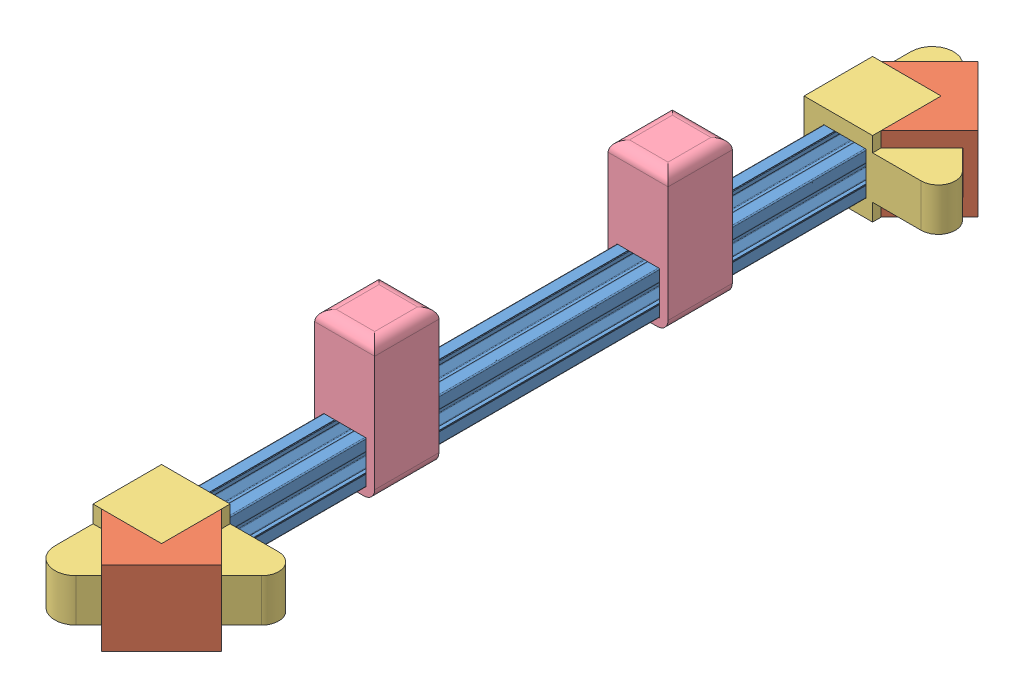
SolidWorks assembly Assem3 - Copy, configuration Varsayılan. Lengths in mm.
Overall size (93.47 78.01 453.33).
9 component instances, 4 part files, 11 mates.
Components (placement in the parent):
- sigma_20x20x1000-1: sigma_20x20x1000 [Varsayılan] at (-144.7646 -85.6017 253.4901) x (0 0 -1) z (1 -0.000076 0) size (350 20 20)
- motortutucular-1: motortutucular [Varsayılan] at (-103.5623 -84.2375 280.9722) x (0.707107 -0.000054 -0.707107) z (-0.707107 0.000054 -0.707107) size (86.65 35 86.65)
  - motortutucuarka-1: motortutucuarka [Varsayılan] at (-25.258 -13.6326 22.249) size (39.6 35 31.98)
  - motortutucuon-1: motortutucuon [Varsayılan] at (-0.4565 -8.6326 49.0416) x (-0.707107 0 0.707107) z (0 1 0) size (62.69 59.86 35)
- motortutucular-2: motortutucular [Varsayılan] at (-103.5625 -86.9722 -123.9919) x (0.707107 -0.000054 0.707107) z (-0.707107 0.000054 0.707107) size (86.65 35 86.65)
  - motortutucuarka-1: motortutucuarka [Varsayılan] at (-25.258 -13.6326 22.249) size (39.6 35 31.98)
  - motortutucuon-1: motortutucuon [Varsayılan] at (-0.4565 -8.6326 49.0416) x (-0.707107 0 0.707107) z (0 1 0) size (62.69 59.86 35)
- ayak-1: ayak [Varsayılan] at (-134.7639 -75.6025 -5.0121) x (-1 0.000076 0) z (0 0 1) size (38 77 30)
- ayak-2: ayak [Varsayılan] at (-134.7639 -75.6025 131.9924) x (-1 0.000076 0) z (0 0 1) size (38 77 30)
Mates (geometry in assembly coordinates):
- Coincident1: coincident anti-aligned: plane of sigma_20x20x1000-1 through (-137.9071 -80.4522 -96.5099) normal (0 0 -1); plane of motortutucular-2/motortutucuon-1 through (-138.562 -75.6022 -96.5099) normal (0 0 1)
- Coincident3: coincident anti-aligned: line of sigma_20x20x1000-1 through (-154.2639 -75.601 -96.5099) axis (1 -0.000076 0); line of motortutucular-2/motortutucuon-1 through (-134.7639 -75.6025 -96.5099) axis (-1 0.000076 0)
- Coincident4: coincident anti-aligned: line of sigma_20x20x1000-1 through (-154.7643 -80.9509 -96.5099) axis (0.000076 1 0); line of motortutucular-2/motortutucuon-1 through (-154.7639 -75.6009 -96.5099) axis (-0.000076 -1 0)
- Coincident5: coincident anti-aligned: plane of sigma_20x20x1000-1 through (-137.9071 -80.4522 253.4901) normal (0 0 1); plane of motortutucular-1/motortutucuon-1 through (-138.5635 -95.6022 253.4901) normal (0 0 -1)
- Coincident6: coincident aligned: line of sigma_20x20x1000-1 through (-149.4154 -95.6013 253.4901) axis (-1 0.000076 0); line of motortutucular-1/motortutucuon-1 through (-134.7654 -95.6025 253.4901) axis (-1 0.000076 0)
- Coincident7: coincident anti-aligned: line of sigma_20x20x1000-1 through (-134.7639 -76.1025 253.4901) axis (-0.000076 -1 0); line of motortutucular-1/motortutucuon-1 through (-134.7654 -95.6025 253.4901) axis (0.000076 1 0)
- Coincident8: coincident: plane of sigma_20x20x1000-1 through (-154.7639 -76.1009 -96.5099) normal (-1 0.000076 0); plane of ayak-1 through (-154.7639 -75.6009 24.9879) normal (1 -0.000076 0)
- Coincident10: coincident: plane of sigma_20x20x1000-1 through (-154.2654 -95.601 -96.5099) normal (-0.000076 -1 0); plane of ayak-1 through (-134.7654 -95.6025 24.9879) normal (0.000076 1 0)
- Coincident11: coincident: plane of sigma_20x20x1000-1 through (-154.765 -90.2509 -96.5099) normal (-1 0.000076 0); plane of ayak-2 through (-154.7639 -75.6009 161.9924) normal (1 -0.000076 0)
- Coincident13: coincident: plane of sigma_20x20x1000-1 through (-154.2654 -95.601 -96.5099) normal (-0.000076 -1 0); plane of ayak-2 through (-134.7654 -95.6025 161.9924) normal (0.000076 1 0)
- Width1: width: plane of ayak-2 through (-134.7639 -75.6025 131.9924) normal (0 0 -1); plane of ayak-1 through (-134.7639 -75.6025 24.9879) normal (0 0 1); plane of motortutucular-2/motortutucuon-1 through (-138.562 -75.6022 -71.5099) normal (0 0 1); plane of motortutucular-1/motortutucuon-1 through (-138.5635 -95.6022 228.4901) normal (0 0 -1)
